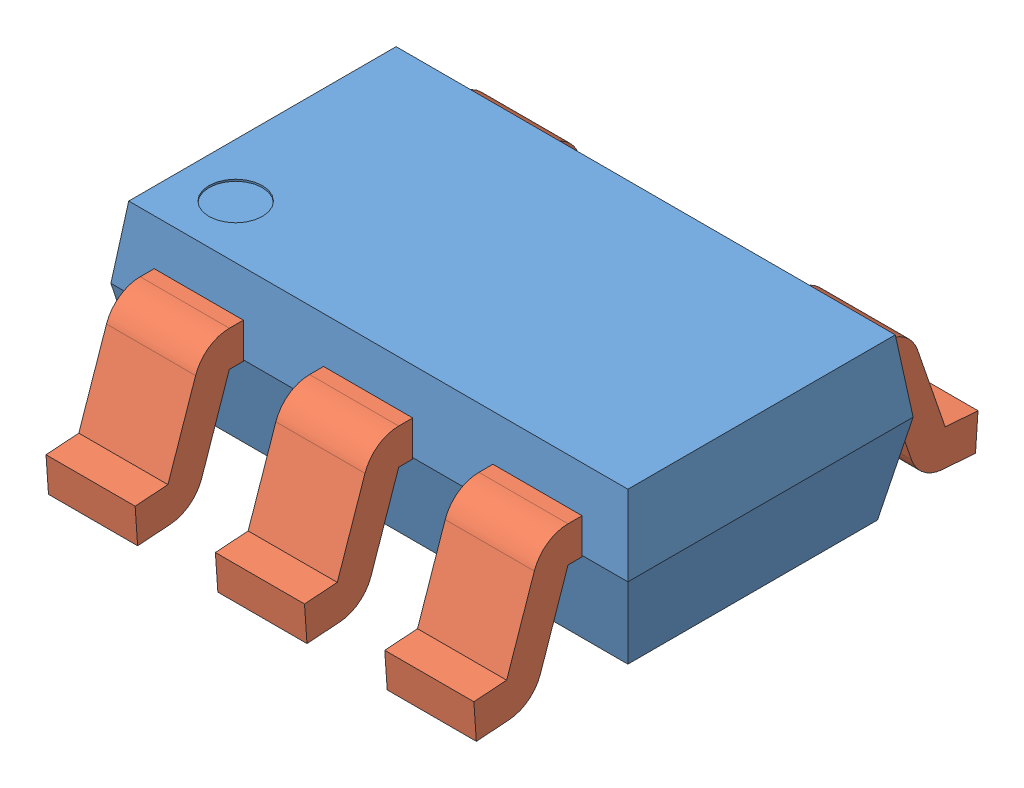
SolidWorks assembly TSOT5 (UJ-5), configuration Default. Lengths in mm.
Overall size (2.9 1 2.83).
6 component instances, 2 part files, 7 mates.
Components (placement in the parent):
- Body-1: Body [Default] at (0 0.1 0) size (2.9 0.9 1.6)
- P-1: P [Default] at (-0.95 0.0998 1.407) x (0 0 -1) z (0 -1 0) size (0.61 0.5 0.8)
- P-2: P [Default] at (0 0.0998 1.407) x (0 0 -1) z (0 -1 0) size (0.61 0.5 0.8)
- P-3: P [Default] at (0.95 0.0998 1.407) x (0 0 -1) z (0 -1 0) size (0.61 0.5 0.8)
- P-4: P [Default] at (-0.95 0.0998 -1.407) x (0 0 1) z (0 -1 0) size (0.61 0.5 0.8)
- P-5: P [Default] at (0.95 0.0998 -1.407) x (0 0 1) z (0 -1 0) size (0.61 0.5 0.8)
Mates (geometry in assembly coordinates):
- Coincident2: coincident: plane of Body-1 through (0 0.1 0) normal (0 0 1); plane of assembly through (0 0 0) normal (0 0 1)
- Coincident3: coincident: plane of Body-1 through (0 0.1 0) normal (1 0 0); plane of assembly through (0 0 0) normal (1 0 0)
- Distance1: distance = 0.1 mm: plane of Body-1 through (0 0.1 0) normal (0 -1 0); plane of assembly through (0 0 0) normal (0 1 0)
- Parallel1: parallel: plane of P-1 through (-0.7 0.5998 0.807) normal (0 0 -1); plane of assembly through (0 0 0) normal (0 0 1)
- Coincident7: coincident: line of P-1 through (-0.7 0 1.4) axis (-1 0 0); plane of assembly
- Distance2: distance = 1.4 mm: line of P-1 through (-0.7 0 1.4) axis (-1 0 0); plane of assembly
- Distance3: distance = 0.95 mm: plane of P-1 through (-0.95 0.0998 1.407) normal (1 0 0); plane of assembly through (0 0 0) normal (1 0 0)
